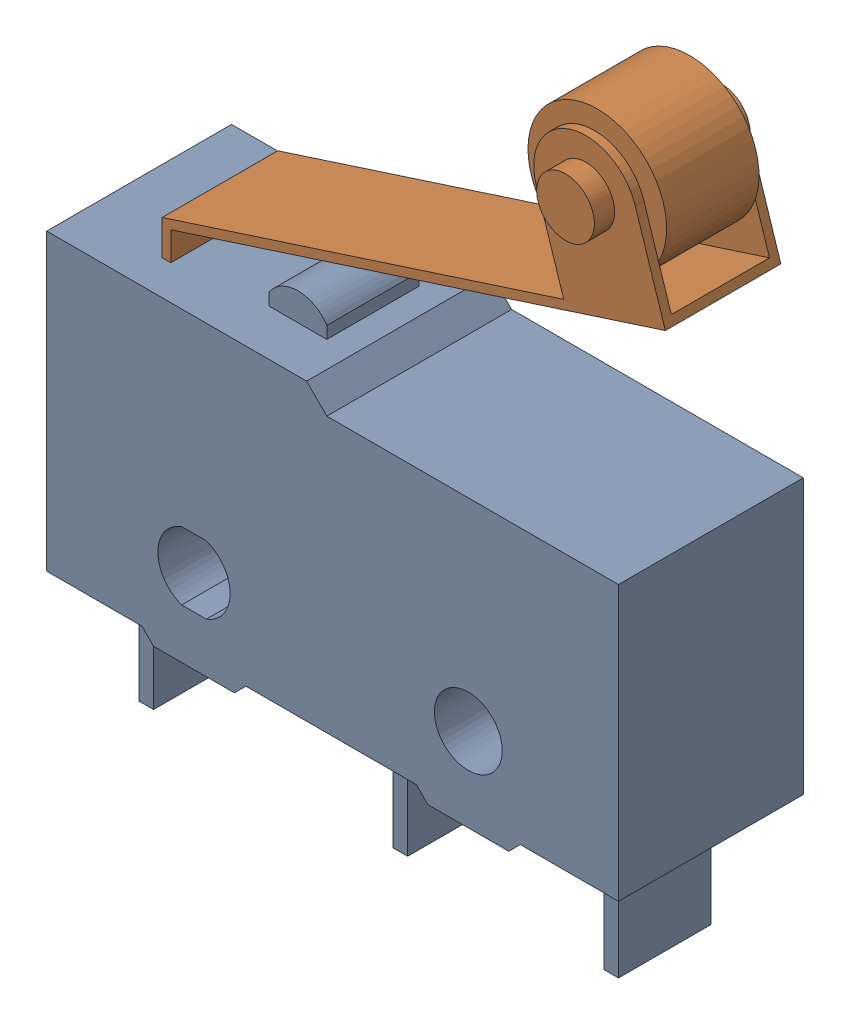
SolidWorks assembly SS_5GL2, configuration Default. Lengths in mm.
Overall size (20.22 25.7 6.4).
2 component instances, 2 part files, 0 mates.
Components (placement in the parent):
- SS_5GL2_BASE-1: SS_5GL2_BASE [Default] at origin size (19.8 15.06 6.4)
- SS_5GL2_ACTUATOR-1: SS_5GL2_ACTUATOR [Default] at (-11.5 7.7 0) size (17.42 11.6 5.4)
